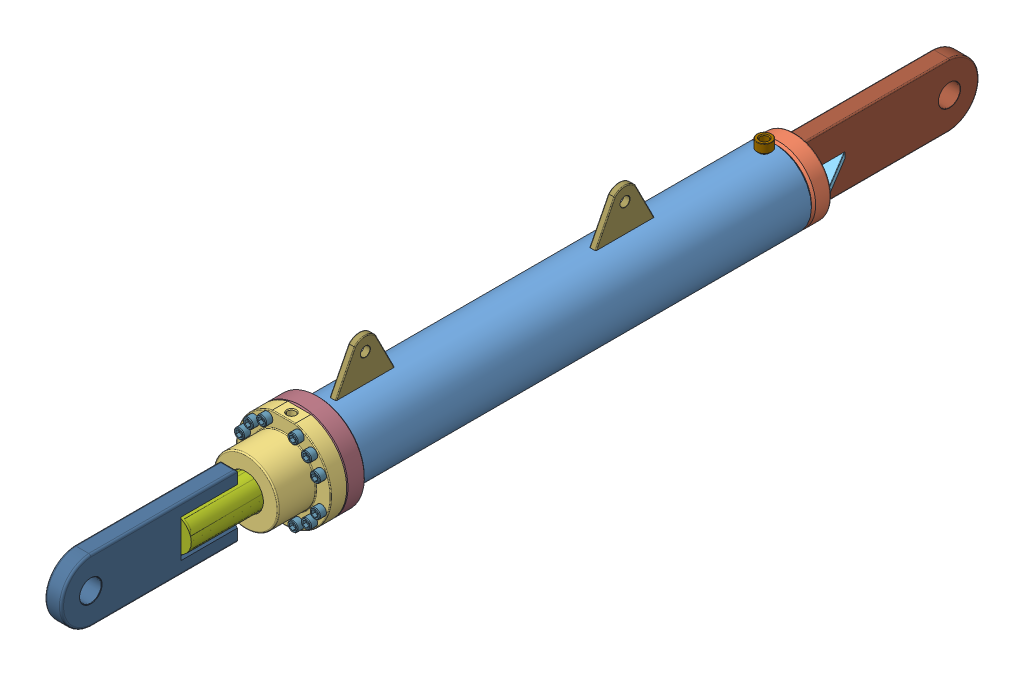
SolidWorks assembly Assembly Of Piston, configuration Default. Lengths in mm.
Overall size (319.61 347.31 2190).
27 component instances, 14 part files, 64 mates.
Components (placement in the parent):
- cylinder-1: cylinder [Default] at origin size (175 175 1140)
- end cap-1: end cap [Default] at (0 0 -586) x (0.999712 -0.023995 0) z (0 0 1) size (175 175 52)
- gland-1: gland [Default] at (0 0 624) size (226 222.6 148)
- half piston-1: half piston [Default] at (0 0 -520) x (-1 0 0) z (0 0 -1) size (138 138 43.7)
- hing2-1: hing2 [Default] at (-20 0 -612) x (-1 0 0) z (0 -1 0) size (60 100 16)
- piston-1: piston [Default] at (0 0 -520) x (-1 0 0) z (0 0 -1) size (138 138 36.3)
- rod-1: rod [Default] at (0 0 154) x (-0.53779 0.843079 0) z (0 0 -1) size (80 80 1428)
- spacer-1: spacer [Default] at (0 0 -465) size (110 110 30)
- stude-1: stude [Default] at (0 100 -540) x (0.957501 0 -0.288429) z (0 1 0) size (35 35 25)
- rod end-1: rod end [Default] at (0 0 811.0842) x (0 0 -1) z (1 0 0) size (420 150 40)
- end cap plate-1: end cap plate [Default] at (0 0 -721.4737) x (0 0 1) z (-1 0 0) size (420 150 40)
- hing2-2: hing2 [Default] at (20 0 -612) x (1 0 0) z (0 1 0) size (60 100 16)
- hing-1: hing [Default] at (0 87.5 -200) x (0 0 -1) z (1 0 0) size (140 100 15.23)
- hing-2: hing [Default] at (0 87.5 420) x (0 0 -1) z (1 0 0) size (140 100 15.23)
- gland flange-1: gland flange [Default] at (0 0 547.5) x (0.707107 0.707107 0) z (0 0 1) size (226 226 45)
- socket head cap screw_am-29: socket head cap screw_am [B18.3.1M - 16 x 2.0 x 80 Hex SHCS -- 44NHX] at (-37.503 90.5402 624) x (0 0 -1) z (1 0 0) size (96 24 24)
- socket head cap screw_am-30: socket head cap screw_am [B18.3.1M - 16 x 2.0 x 80 Hex SHCS -- 44NHX] at (-69.2965 69.2965 624) x (0 0 -1) z (1 0 0) size (96 24 24)
- socket head cap screw_am-31: socket head cap screw_am [B18.3.1M - 16 x 2.0 x 80 Hex SHCS -- 44NHX] at (-90.5402 37.503 624) x (0 0 -1) z (1 0 0) size (96 24 24)
- socket head cap screw_am-32: socket head cap screw_am [B18.3.1M - 16 x 2.0 x 80 Hex SHCS -- 44NHX] at (-90.5402 -37.503 624) x (0 0 -1) z (1 0 0) size (96 24 24)
- socket head cap screw_am-33: socket head cap screw_am [B18.3.1M - 16 x 2.0 x 80 Hex SHCS -- 44NHX] at (-69.2965 -69.2965 624) x (0 0 -1) z (1 0 0) size (96 24 24)
- socket head cap screw_am-34: socket head cap screw_am [B18.3.1M - 16 x 2.0 x 80 Hex SHCS -- 44NHX] at (-37.503 -90.5402 624) x (0 0 -1) z (1 0 0) size (96 24 24)
- socket head cap screw_am-35: socket head cap screw_am [B18.3.1M - 16 x 2.0 x 80 Hex SHCS -- 44NHX] at (37.503 -90.5402 624) x (0 0 -1) z (1 0 0) size (96 24 24)
- socket head cap screw_am-36: socket head cap screw_am [B18.3.1M - 16 x 2.0 x 80 Hex SHCS -- 44NHX] at (69.2965 -69.2965 624) x (0 0 -1) z (1 0 0) size (96 24 24)
- socket head cap screw_am-37: socket head cap screw_am [B18.3.1M - 16 x 2.0 x 80 Hex SHCS -- 44NHX] at (90.5402 -37.503 624) x (0 0 -1) z (1 0 0) size (96 24 24)
- socket head cap screw_am-38: socket head cap screw_am [B18.3.1M - 16 x 2.0 x 80 Hex SHCS -- 44NHX] at (90.5402 37.503 624) x (0 0 -1) z (1 0 0) size (96 24 24)
- socket head cap screw_am-39: socket head cap screw_am [B18.3.1M - 16 x 2.0 x 80 Hex SHCS -- 44NHX] at (37.503 90.5402 624) x (0 0 -1) z (1 0 0) size (96 24 24)
- socket head cap screw_am-40: socket head cap screw_am [B18.3.1M - 16 x 2.0 x 80 Hex SHCS -- 44NHX] at (69.2965 69.2965 624) x (0 0 -1) z (1 0 0) size (96 24 24)
Mates (geometry in assembly coordinates):
- Coincident1: coordinate: point of cylinder-1; point of assembly
- Concentric1: concentric: cylinder of cylinder-1 through (0 0 570) axis (0 0 -1) radius 87.5; cylinder of end cap-1 through (0 0 -570) axis (0 0 1) radius 70
- Coincident2: coincident: plane of cylinder-1 through (0 0 -570) normal (0 0 -1); plane of end cap-1 through (0 0 -570) normal (0 0 1)
- Concentric2: concentric: cylinder of cylinder-1 through (0 102 -540) axis (0 -1 0) radius 5; cylinder of stude-1 through (0 112.5 -540) axis (0 1 0) radius 9.4869
- Tangent1: tangent: cylinder of cylinder-1 through (0 0 570) axis (0 0 -1) radius 87.5; plane of stude-1 through (0 87.5 -540) normal (0 -1 0)
- Concentric3: concentric: cylinder of cylinder-1 through (0 0 570) axis (0 0 -1) radius 70; cylinder of gland-1 through (0 0 570) axis (0 0 -1) radius 70
- Coincident3: coincident: plane of cylinder-1 through (0 0 570) normal (0 0 1); plane of gland-1 through (0 0 570) normal (0 0 -1)
- Coincident4: coincident: plane of gland-1 through (0 0 624) normal (1 0 0); plane of assembly through (0 0 0) normal (1 0 0)
- Concentric4: concentric: cylinder of piston-1 through (0 0 -520) axis (0 0 -1) radius 34; cylinder of rod-1 through (0 0 154) axis (0 0 1) radius 34
- Coincident5: coincident: plane of piston-1 through (0 0 -480) normal (0 0 1); plane of rod-1 through (29.5078 18.8227 -480) normal (0 0 -1)
- Concentric5: concentric: cylinder of half piston-1 through (0 0 -520) axis (0 0 -1) radius 33; cylinder of rod-1 through (0 0 154) axis (0 0 1) radius 34
- Coincident6: coincident: plane of half piston-1 through (60 0 -516.3) normal (0 0 1); plane of piston-1 through (75.5299 -86 -516.3) normal (0 0 -1)
- Concentric6: concentric: cylinder of cylinder-1 through (0 0 570) axis (0 0 -1) radius 87.5; cylinder of rod-1 through (0 0 -560) axis (0 0 1) radius 40
- Concentric7: concentric: cylinder of rod-1 through (0 0 -560) axis (0 0 1) radius 40; cylinder of spacer-1 through (0 0 -450) axis (0 0 -1) radius 40
- Coincident7: coincident: plane of piston-1 through (0 0 -480) normal (0 0 1); plane of spacer-1 through (0 0 -480) normal (0 0 -1)
- Coincident8: coincident: plane of rod end-1 through (0 0 811.0842) normal (0 1 0); plane of assembly through (0 0 0) normal (0 1 0)
- Coincident9: coincident: plane of rod end-1 through (0 0 811.0842) normal (1 0 0); plane of assembly through (0 0 0) normal (1 0 0)
- Coincident10: coincident: plane of rod-1 through (0 0 868) normal (0 0 1); plane of rod end-1 through (20 40 868) normal (0 0 -1)
- Coincident11: coincident: plane of end cap plate-1 through (0 0 -721.4737) normal (0 1 0); plane of assembly through (0 0 0) normal (0 1 0)
- Coincident12: coincident: plane of end cap plate-1 through (0 0 -721.4737) normal (-1 0 0); plane of assembly through (0 0 0) normal (1 0 0)
- Coincident13: coincident: plane of end cap-1 through (0 0 -612) normal (0 0 -1); plane of end cap plate-1 through (-20 75 -612) normal (0 0 1)
- Coincident14: coincident: plane of rod end-1 through (20 0 1082.8214) normal (1 0 0); plane of end cap plate-1 through (20 0 -956.8214) normal (1 0 0)
- Coincident15: coincident: plane of end cap-1 through (0 0 -560) normal (0 0 1); plane of half piston-1 through (0 0 -560) normal (0 0 -1)
- Coincident16: coincident: plane of end cap-1 through (0 0 -612) normal (0 0 -1); plane of hing2-1 through (-20 -8 -612) normal (0 0 1)
- Coincident17: coincident: plane of hing2-1 through (-20 -8 -712) normal (1 0 0); plane of end cap plate-1 through (-20 0 -956.8214) normal (-1 0 0)
- Coincident18: coincident: plane of hing2-1 through (-20 0 -612) normal (0 -1 0); plane of assembly through (0 0 0) normal (0 1 0)
- Tangent2: tangent: cylinder of cylinder-1 through (0 0 570) axis (0 0 -1) radius 87.5; plane of ? through (-7.5 87.5 -459.9121) normal (0 -1 0)
- Coincident19: coincident: plane of ? through (0 87.5 -389.9121) normal (-1 0 0); plane of assembly through (0 0 0) normal (1 0 0)
- Coincident21: coincident: plane of end cap-1 through (0 0 -612) normal (0 0 -1); plane of hing2-2 through (20 8 -612) normal (0 0 1)
- Coincident22: coincident: plane of end cap plate-1 through (20 0 -956.8214) normal (1 0 0); plane of hing2-2 through (20 8 -712) normal (-1 0 0)
- Coincident24: coincident: plane of hing2-2 through (20 0 -612) normal (0 1 0); plane of assembly through (0 0 0) normal (0 1 0)
- Tangent4: tangent: cylinder of cylinder-1 through (0 0 570) axis (0 0 -1) radius 87.5; plane of hing-1 through (7.5 87.5 -130) normal (0 -1 0)
- Tangent5: tangent: cylinder of cylinder-1 through (0 0 570) axis (0 0 -1) radius 87.5; plane of hing-2 through (7.5 87.5 490) normal (0 -1 0)
- Coincident25: coincident: plane of hing-1 through (0 87.5 -200) normal (1 0 0); plane of assembly through (0 0 0) normal (1 0 0)
- Coincident26: coincident: plane of hing-2 through (0 87.5 420) normal (1 0 0); plane of assembly through (0 0 0) normal (1 0 0)
- Distance2: distance = 420 mm: plane of hing-2 through (0 87.5 420) normal (0 0 -1); plane of assembly through (0 0 0) normal (0 0 1)
- Distance3: distance = 200 mm: plane of hing-1 through (0 87.5 -200) normal (0 0 -1); plane of assembly through (0 0 0) normal (0 0 1)
- Concentric10: concentric: cylinder of cylinder-1 through (0 0 0) axis (0 0 -1) radius 84; cylinder of gland flange-1 through (0 0 570) axis (0 0 -1) radius 83
- Concentric11: concentric: cylinder of gland-1 through (-90.5402 37.503 550) axis (0 0 1) radius 8.5; cylinder of gland flange-1 through (-90.5402 37.503 570) axis (0 0 1) radius 7
- Coincident29: coincident: plane of gland-1 through (0 0 570) normal (0 0 -1); plane of gland flange-1 through (0 0 570) normal (0 0 1)
- Concentric12: concentric: cylinder of gland-1 through (-37.503 90.5402 550) axis (0 0 1) radius 8.5; cylinder of socket head cap screw_am-29 through (-37.503 90.5402 655.75) axis (0 0 1) radius 12
- Coincident30: coincident: plane of gland-1 through (0 154.6191 608) normal (0 0 1); plane of socket head cap screw_am-29 through (-37.503 102.5402 608) normal (0 0 -1)
- Concentric13: concentric: cylinder of gland-1 through (-69.2965 69.2965 550) axis (0 0 1) radius 8.5; cylinder of socket head cap screw_am-30 through (-69.2965 69.2965 655.75) axis (0 0 1) radius 12
- Coincident31: coincident: plane of gland-1 through (0 154.6191 608) normal (0 0 1); plane of socket head cap screw_am-30 through (-69.2965 81.2965 608) normal (0 0 -1)
- Concentric14: concentric: cylinder of gland-1 through (-90.5402 37.503 550) axis (0 0 1) radius 8.5; cylinder of socket head cap screw_am-31 through (-90.5402 37.503 655.75) axis (0 0 1) radius 12
- Coincident32: coincident: plane of gland-1 through (0 154.6191 608) normal (0 0 1); plane of socket head cap screw_am-31 through (-90.5402 49.503 608) normal (0 0 -1)
- Concentric15: concentric: cylinder of gland-1 through (-90.5402 -37.503 550) axis (0 0 1) radius 8.5; cylinder of socket head cap screw_am-32 through (-90.5402 -37.503 655.75) axis (0 0 1) radius 12
- Coincident33: coincident: plane of gland-1 through (0 154.6191 608) normal (0 0 1); plane of socket head cap screw_am-32 through (-90.5402 -25.503 608) normal (0 0 -1)
- Concentric16: concentric: cylinder of gland-1 through (-69.2965 -69.2965 550) axis (0 0 1) radius 8.5; cylinder of socket head cap screw_am-33 through (-69.2965 -69.2965 655.75) axis (0 0 1) radius 12
- Coincident34: coincident: plane of gland-1 through (0 154.6191 608) normal (0 0 1); plane of socket head cap screw_am-33 through (-69.2965 -57.2965 608) normal (0 0 -1)
- Concentric17: concentric: cylinder of gland-1 through (-37.503 -90.5402 550) axis (0 0 1) radius 8.5; cylinder of socket head cap screw_am-34 through (-37.503 -90.5402 655.75) axis (0 0 1) radius 12
- Coincident35: coincident: plane of gland-1 through (0 154.6191 608) normal (0 0 1); plane of socket head cap screw_am-34 through (-37.503 -78.5402 608) normal (0 0 -1)
- Concentric18: concentric: cylinder of gland-1 through (37.503 -90.5402 550) axis (0 0 1) radius 8.5; cylinder of socket head cap screw_am-35 through (37.503 -90.5402 655.75) axis (0 0 1) radius 12
- Coincident36: coincident: plane of gland-1 through (0 154.6191 608) normal (0 0 1); plane of socket head cap screw_am-35 through (37.503 -78.5402 608) normal (0 0 -1)
- Concentric19: concentric: cylinder of gland-1 through (69.2965 -69.2965 550) axis (0 0 1) radius 8.5; cylinder of socket head cap screw_am-36 through (69.2965 -69.2965 655.75) axis (0 0 1) radius 12
- Coincident37: coincident: plane of gland-1 through (0 154.6191 608) normal (0 0 1); plane of socket head cap screw_am-36 through (69.2965 -57.2965 608) normal (0 0 -1)
- Concentric20: concentric: cylinder of gland-1 through (90.5402 -37.503 550) axis (0 0 1) radius 8.5; cylinder of socket head cap screw_am-37 through (90.5402 -37.503 655.75) axis (0 0 1) radius 12
- Coincident38: coincident: plane of gland-1 through (0 154.6191 608) normal (0 0 1); plane of socket head cap screw_am-37 through (90.5402 -25.503 608) normal (0 0 -1)
- Concentric21: concentric: cylinder of gland-1 through (90.5402 37.503 550) axis (0 0 1) radius 8.5; cylinder of socket head cap screw_am-38 through (90.5402 37.503 655.75) axis (0 0 1) radius 12
- Coincident39: coincident: plane of gland-1 through (0 154.6191 608) normal (0 0 1); plane of socket head cap screw_am-38 through (90.5402 49.503 608) normal (0 0 -1)
- Concentric22: concentric: cylinder of gland-1 through (37.503 90.5402 550) axis (0 0 1) radius 8.5; cylinder of socket head cap screw_am-39 through (37.503 90.5402 655.75) axis (0 0 1) radius 12
- Coincident40: coincident: plane of gland-1 through (0 154.6191 608) normal (0 0 1); plane of socket head cap screw_am-39 through (37.503 102.5402 608) normal (0 0 -1)
- Concentric23: concentric: cylinder of gland-1 through (69.2965 69.2965 550) axis (0 0 1) radius 8.5; cylinder of socket head cap screw_am-40 through (69.2965 69.2965 655.75) axis (0 0 1) radius 12
- Coincident41: coincident: plane of gland-1 through (0 154.6191 608) normal (0 0 1); plane of socket head cap screw_am-40 through (69.2965 81.2965 608) normal (0 0 -1)
